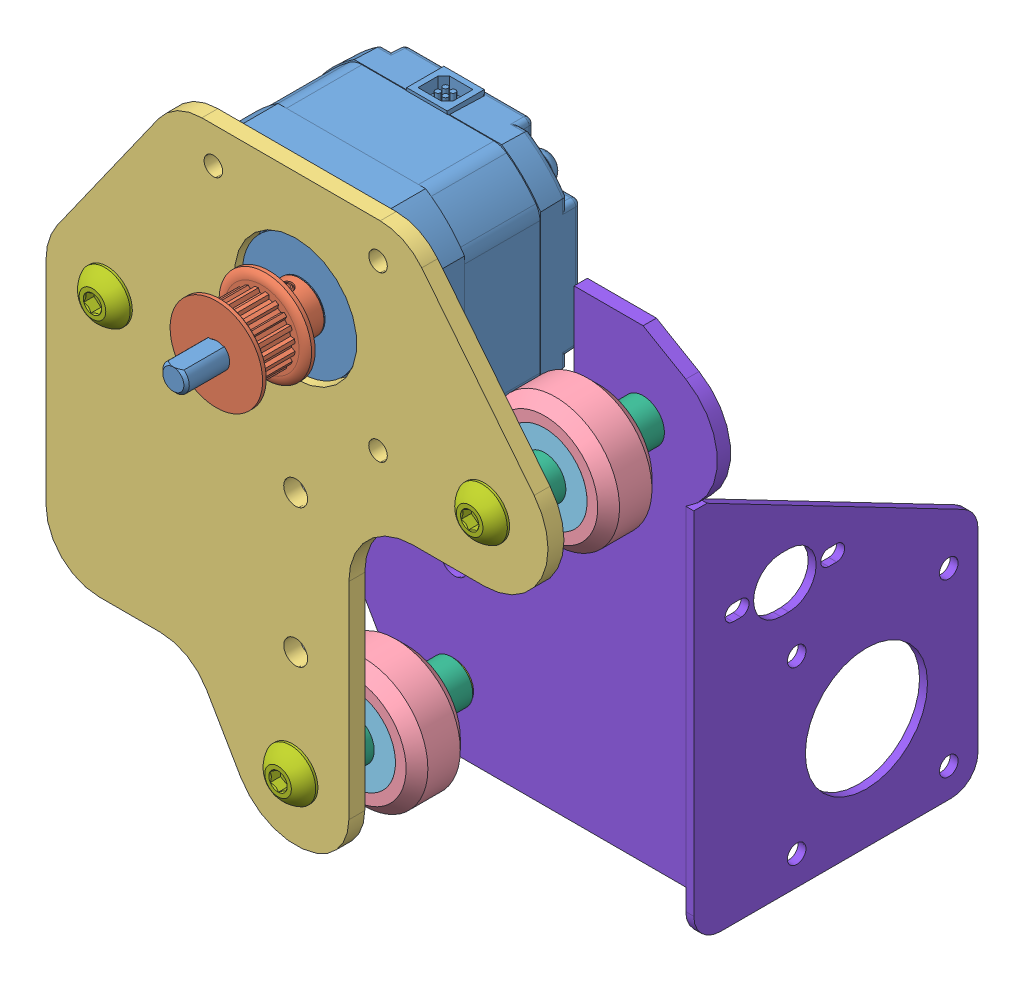
SolidWorks assembly Assem53, configuration Default. Lengths in mm.
Overall size (99.39 118.76 106.43).
29 component instances, 10 part files, 23 mates.
Components (placement in the parent):
- 6627T65_Position-Control DC Motor-1: 6627T65_Position-Control DC Motor [6627T65] at (61.1977 36.0894 18.3845) size (42.42 42.97 55.75)
- 1375K118_MXL Series Timing Belt Pulley-1: 1375K118_MXL Series Timing Belt Pulley [1375K118] at (61.1977 36.0894 28.3665) x (0 0 1) z (-1 0 0) size (15.9 17.4 17.4)
- x motor bracket-1: x motor bracket [Default] at (25.8494 40.6815 18.3845) x (0 -1 0) z (0 0 1) size (109.76 94.5 3)
- Longer screw assembly-1: Longer screw assembly [Default] at (103.8211 32.1386 -15.7049) x (-0.984674 0.174405 0) z (0 0 1) size (24.1 24.1 43.38)
  - roller_rubber-1: roller_rubber [Default] at (5.0143 12.5185 20.6394) size (24.1 24.1 10.2)
  - Bearing for Roller-1: Bearing for Roller [Default] at (5.0143 12.5185 15.5394) size (16 16 2)
  - Bearing for Roller-2: Bearing for Roller [Default] at (5.0143 12.5185 23.7394) size (16 16 2)
  - Roller Spacer-3: Roller Spacer [Default] at (5.0143 12.5185 25.7394) x (-0.5689 0.822407 0) z (0 0 1) size (8 8 8.35)
  - Roller Spacer-4: Roller Spacer [Default] at (5.0143 12.5185 7.1894) x (-0.029804 -0.999556 0) z (0 0 1) size (8 8 8.35)
  - 92095A222_Button Head Hex Drive Screw-1: 92095A222_Button Head Hex Drive Screw [92095A222] at (5.0143 12.5185 39.8394) x (0.476595 0.879123 0) z (0 0 1) size (9.5 9.5 43.38)
- E-Motor Bracket-1: E-Motor Bracket [Default] at (61.2004 -39.1189 -11.0155) x (0 -1 0) z (0 0 1) size (96.5 94.74 53.5)
- 91828A241_18-8 Stainless Steel Hex Nut-1: 91828A241_18-8 Stainless Steel Hex Nut [91828A241] at (96.7004 20.6865 -13.0155) size (8 9.24 4.46)
- Longer screw assembly-2: Longer screw assembly [Default] at (18.0394 9.3841 -15.7049) x (0.975194 -0.221352 0) z (0 0 1) size (24.1 24.1 43.38)
  - roller_rubber-1: roller_rubber [Default] at (5.0143 12.5185 20.6394) size (24.1 24.1 10.2)
  - Bearing for Roller-1: Bearing for Roller [Default] at (5.0143 12.5185 15.5394) size (16 16 2)
  - Bearing for Roller-2: Bearing for Roller [Default] at (5.0143 12.5185 23.7394) size (16 16 2)
  - Roller Spacer-3: Roller Spacer [Default] at (5.0143 12.5185 25.7394) x (-0.5689 0.822407 0) z (0 0 1) size (8 8 8.35)
  - Roller Spacer-4: Roller Spacer [Default] at (5.0143 12.5185 7.1894) x (-0.029804 -0.999556 0) z (0 0 1) size (8 8 8.35)
  - 92095A222_Button Head Hex Drive Screw-1: 92095A222_Button Head Hex Drive Screw [92095A222] at (5.0143 12.5185 39.8394) x (0.476595 0.879123 0) z (0 0 1) size (9.5 9.5 43.38)
- 91828A241_18-8 Stainless Steel Hex Nut-2: 91828A241_18-8 Stainless Steel Hex Nut [91828A241] at (25.6804 20.6865 -13.0155) size (8 9.24 4.46)
- Longer screw assembly-3: Longer screw assembly [Default] at (55.6157 -52.4318 -15.7049) size (24.1 24.1 43.38)
  - roller_rubber-1: roller_rubber [Default] at (5.0143 12.5185 20.6394) size (24.1 24.1 10.2)
  - Bearing for Roller-1: Bearing for Roller [Default] at (5.0143 12.5185 15.5394) size (16 16 2)
  - Bearing for Roller-2: Bearing for Roller [Default] at (5.0143 12.5185 23.7394) size (16 16 2)
  - Roller Spacer-3: Roller Spacer [Default] at (5.0143 12.5185 25.7394) x (-0.5689 0.822407 0) z (0 0 1) size (8 8 8.35)
  - Roller Spacer-4: Roller Spacer [Default] at (5.0143 12.5185 7.1894) x (-0.029804 -0.999556 0) z (0 0 1) size (8 8 8.35)
  - 92095A222_Button Head Hex Drive Screw-1: 92095A222_Button Head Hex Drive Screw [92095A222] at (5.0143 12.5185 39.8394) x (0.476595 0.879123 0) z (0 0 1) size (9.5 9.5 43.38)
- 93475A240_18-8 Stainless Steel Washer-1: 93475A240_18-8 Stainless Steel Washer [93475A240] at (60.6301 -39.9133 -12.1155) size (10 10 1.1)
- 91828A241_18-8 Stainless Steel Hex Nut-3: 91828A241_18-8 Stainless Steel Hex Nut [91828A241] at (60.6301 -39.9133 -14.1155) size (8 9.24 4.46)
Mates (geometry in assembly coordinates):
- Concentric12: concentric aligned: circle of 6627T65_Position-Control DC Motor-1; circle of 1375K118_MXL Series Timing Belt Pulley-1
- Coincident21: coincident anti-aligned: plane of 6627T65_Position-Control DC Motor-1 through (61.1977 36.0894 20.4165) normal (0 0 1); plane of 1375K118_MXL Series Timing Belt Pulley-1 through (61.1977 34.0894 20.4165) normal (0 0 -1)
- Concentric13: concentric aligned: circle of 6627T65_Position-Control DC Motor-1; circle of x motor bracket-1
- Coincident23: coincident anti-aligned: plane of 6627T65_Position-Control DC Motor-1 through (61.1977 36.0894 18.3845) normal (0 0 1); plane of x motor bracket-1 through (96.7005 20.5865 18.3845) normal (0 0 -1)
- Parallel4: parallel anti-aligned: line of 6627T65_Position-Control DC Motor-1 through (47.3139 57.2984 17.8765) axis (1 0 0); line of x motor bracket-1 through (77.11 58.3494 18.3845) axis (-1 0 0)
- Concentric14: concentric aligned: circle of x motor bracket-1; circle of Longer screw assembly-1/Roller Spacer-3
- Coincident26: coincident anti-aligned: plane of x motor bracket-1 through (96.7005 20.5865 18.3845) normal (0 0 -1); plane of Longer screw assembly-2/Roller Spacer-3 through (25.7004 20.4822 18.3845) normal (0 0 1)
- Concentric16: concentric aligned: circle of x motor bracket-1; circle of Longer screw assembly-2/Roller Spacer-3
- Coincident27: coincident anti-aligned: plane of x motor bracket-1 through (96.7005 20.5865 18.3845) normal (0 0 -1); plane of Longer screw assembly-3/Roller Spacer-3 through (60.6301 -39.9133 18.3845) normal (0 0 1)
- Concentric17: concentric aligned: circle of x motor bracket-1; circle of Longer screw assembly-3/Roller Spacer-3
- Coincident29: coincident anti-aligned: plane of x motor bracket-1 through (96.7005 20.5865 18.3845) normal (0 0 -1); plane of Longer screw assembly-1/Roller Spacer-3 through (96.7004 20.6865 18.3845) normal (0 0 1)
- Coincident30: coincident anti-aligned: plane of Longer screw assembly-1/Roller Spacer-4 through (96.7004 20.6865 -8.5155) normal (0 0 -1); plane of E-Motor Bracket-1 through (98.677 21.0338 -8.5155) normal (0 0 1)
- Concentric18: concentric aligned: circle of Longer screw assembly-1/Roller Spacer-4; circle of E-Motor Bracket-1
- Coincident31: coincident anti-aligned: plane of E-Motor Bracket-1 through (98.677 21.0338 -8.5155) normal (0 0 1); plane of Longer screw assembly-3/Roller Spacer-4 through (60.6301 -39.9133 -8.5155) normal (0 0 -1)
- Parallel5: parallel aligned: line of E-Motor Bracket-1 through (38.7004 13.5865 -11.0155) axis (0 1 0); line of 6627T65_Position-Control DC Motor-1 through (41.243 24.9228 -11.3335) axis (0 1 0)
- Coincident33: coincident anti-aligned: plane of E-Motor Bracket-1 through (98.677 21.0338 -11.0155) normal (0 0 -1); plane of 91828A241_18-8 Stainless Steel Hex Nut-2 through (21.6804 22.9959 -11.0155) normal (0 0 1)
- Concentric26: concentric aligned: circle of E-Motor Bracket-1; circle of 91828A241_18-8 Stainless Steel Hex Nut-2
- Coincident34: coincident anti-aligned: plane of E-Motor Bracket-1 through (98.677 21.0338 -11.0155) normal (0 0 -1); plane of 91828A241_18-8 Stainless Steel Hex Nut-1 through (92.7004 22.9959 -11.0155) normal (0 0 1)
- Concentric27: concentric aligned: circle of E-Motor Bracket-1; circle of 91828A241_18-8 Stainless Steel Hex Nut-1
- Coincident40: coincident anti-aligned: plane of E-Motor Bracket-1 through (98.677 21.0338 -11.0155) normal (0 0 -1); plane of 93475A240_18-8 Stainless Steel Washer-1 through (60.6301 -39.9133 -11.0155) normal (0 0 1)
- Concentric28: concentric aligned: circle of Longer screw assembly-3/Roller Spacer-4; circle of 93475A240_18-8 Stainless Steel Washer-1
- Coincident41: coincident anti-aligned: plane of 93475A240_18-8 Stainless Steel Washer-1 through (60.6301 -39.9133 -12.1155) normal (0 0 -1); plane of 91828A241_18-8 Stainless Steel Hex Nut-3 through (56.6301 -37.6039 -12.1155) normal (0 0 1)
- Concentric30: concentric aligned: circle of 93475A240_18-8 Stainless Steel Washer-1; circle of 91828A241_18-8 Stainless Steel Hex Nut-3
